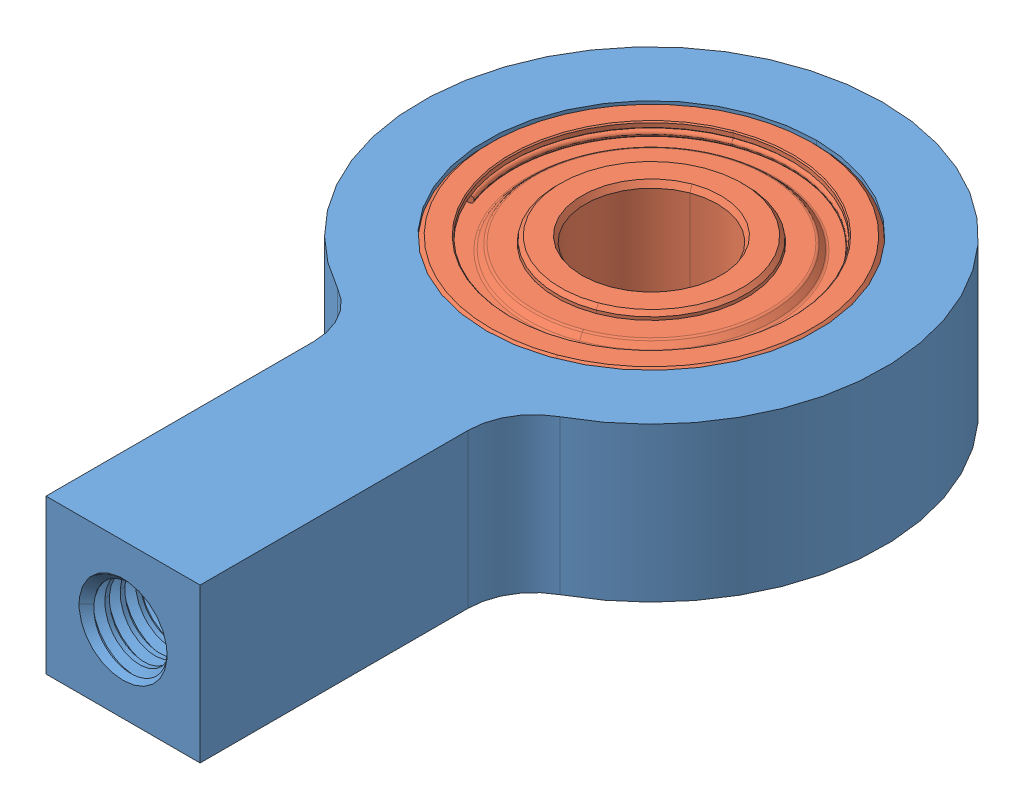
SolidWorks assembly 1605-0024-0006 Assembly, configuration Default. Lengths in mm.
Overall size (21 7 34.5).
3 component instances, 2 part files, 0 mates.
Components (placement in the parent):
- 1605-0024-0006 Assembly.STEP-1: 1605-0024-0006 Assembly.STEP [Default] at origin size (21 7 34.5)
  - 1605-0024-0006.STEP-1: 1605-0024-0006.STEP [Default] at (-36.6519 9.1529 3.8756) size (21 7 34.5)
  - 1600-0515-0006.STEP-1: 1600-0515-0006.STEP [Default] at (-36.6519 11.1529 3.8756) x (0.936051 0 -0.351863) z (0.351863 0 0.936051) size (15 5 15)
